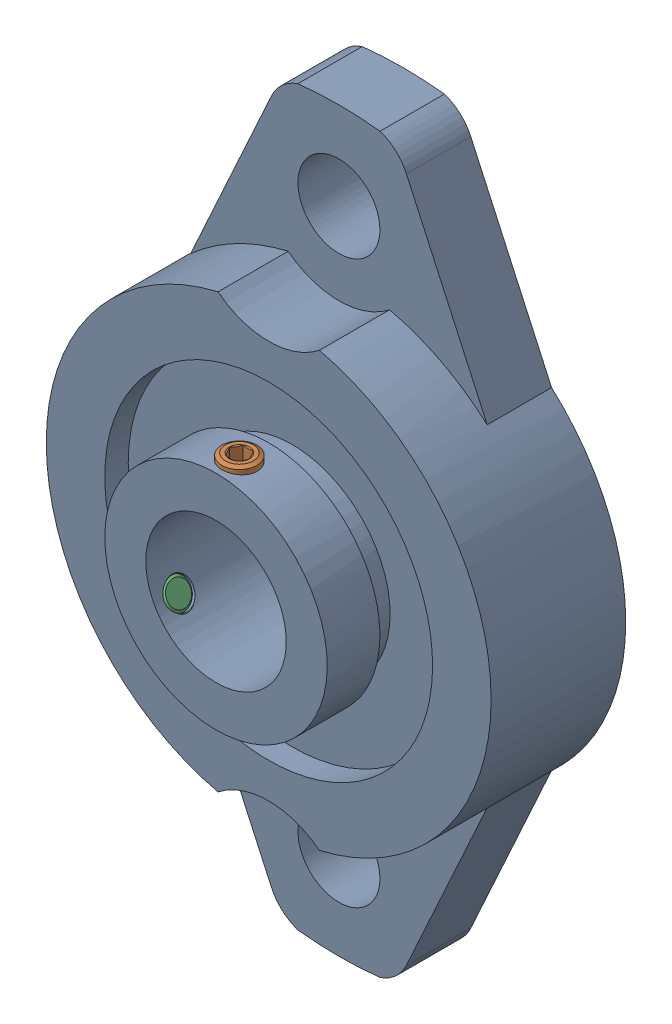
SolidWorks assembly HBT12, configuration Default. Lengths in mm.
Overall size (38 63 16.46).
3 component instances, 2 part files, 0 mates.
Components (placement in the parent):
- HBT12x-1: HBT12x [Default] at origin size (38 63 16.46)
- Hexagon socket set screw with flat point DIN 913 - M3x4-1: Hexagon socket set screw with flat point DIN 913 - M3x4 [Default] at (0 10 6) x (0 -1 0) z (-1 0 0) size (4.01 3.07 3.07)
- Hexagon socket set screw with flat point DIN 913 - M3x4-2: Hexagon socket set screw with flat point DIN 913 - M3x4 [Default] at (-8.6603 -5 6) x (0.866025 0.5 0) z (-0.5 0.866025 0) size (4.01 3.07 3.07)
